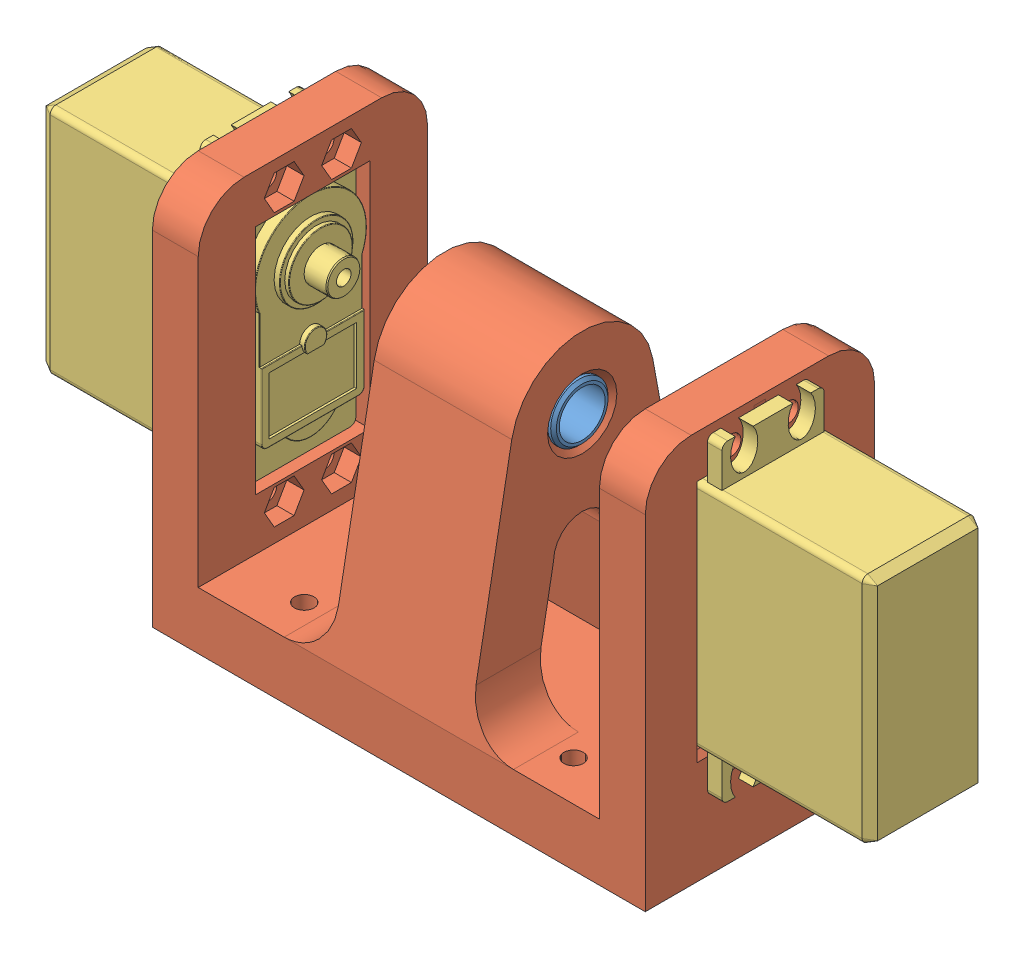
SolidWorks assembly AssemblyShoulderJoint, configuration По умолчанию. Lengths in mm.
Overall size (145.08 68 40).
5 component instances, 3 part files, 11 mates.
Components (placement in the parent):
- sleeve-1: sleeve [По умолчанию] at (12 39.75 0) x (0 0 1) z (-1 0 0) size (10 10 12)
- sleeve-2: sleeve [По умолчанию] at (0 39.75 0) x (0 -0.171125 0.985249) z (-1 0 0) size (10 10 12)
- ShoulderJoint-1: ShoulderJoint [По умолчанию] at origin size (86 68 40)
- MG995-1: MG995 [預設] at (-45.54 9 -9.5) x (0 1 0) z (0 0 -1) size (54.5 43.19 19.5)
- MG995-2: MG995 [預設] at (45.54 9 10) x (0 1 0) z (0 0 1) size (54.5 43.19 19.5)
Mates (geometry in assembly coordinates):
- Концентричный1: concentric anti-aligned: cylinder of sleeve-1 through (0 39.75 0) axis (1 0 0) radius 5; cylinder of ShoulderJoint-1 through (70.4557 39.75 0) axis (-1 0 0) radius 5.05
- Совпадение1: coincident aligned: plane of sleeve-1 through (12 39.75 0) normal (1 0 0); plane of ShoulderJoint-1 through (12 0 20) normal (1 0 0)
- Концентричный2: concentric anti-aligned: cylinder of sleeve-2 through (-12 39.75 0) axis (1 0 0) radius 5; cylinder of ShoulderJoint-1 through (70.4557 39.75 0) axis (-1 0 0) radius 5.05
- Совпадение2: coincident aligned: plane of sleeve-2 through (-12 39.75 0) normal (-1 0 0); plane of ShoulderJoint-1 through (-12 0 20) normal (-1 0 0)
- Совпадение3: coordinate: point of ShoulderJoint-1; point of assembly
- Совпадение4: coincident anti-aligned: plane of ShoulderJoint-1 through (-10.1691 0 10) normal (0 0 -1); plane of MG995-2 through (37 9 10) normal (0 0 1)
- Совпадение5: coincident anti-aligned: plane of ShoulderJoint-1 through (43 0 20) normal (1 0 0); plane of MG995-2 through (43 9 0.875) normal (-1 0 0)
- Совпадение6: coincident anti-aligned: plane of ShoulderJoint-1 through (-10.1691 9 0) normal (0 1 0); plane of MG995-2 through (37 9 10) normal (0 -1 0)
- Совпадение7: coincident anti-aligned: plane of ShoulderJoint-1 through (10.1691 0 10) normal (0 0 -1); plane of MG995-1 through (-37 9 10) normal (0 0 1)
- Совпадение8: coincident anti-aligned: plane of ShoulderJoint-1 through (-43 0 20) normal (-1 0 0); plane of MG995-1 through (-43 49.5 -0.375) normal (1 0 0)
- Совпадение9: coincident anti-aligned: plane of ShoulderJoint-1 through (10.1691 49.5 0) normal (0 -1 0); plane of MG995-1 through (-37 49.5 -9.5) normal (0 1 0)
